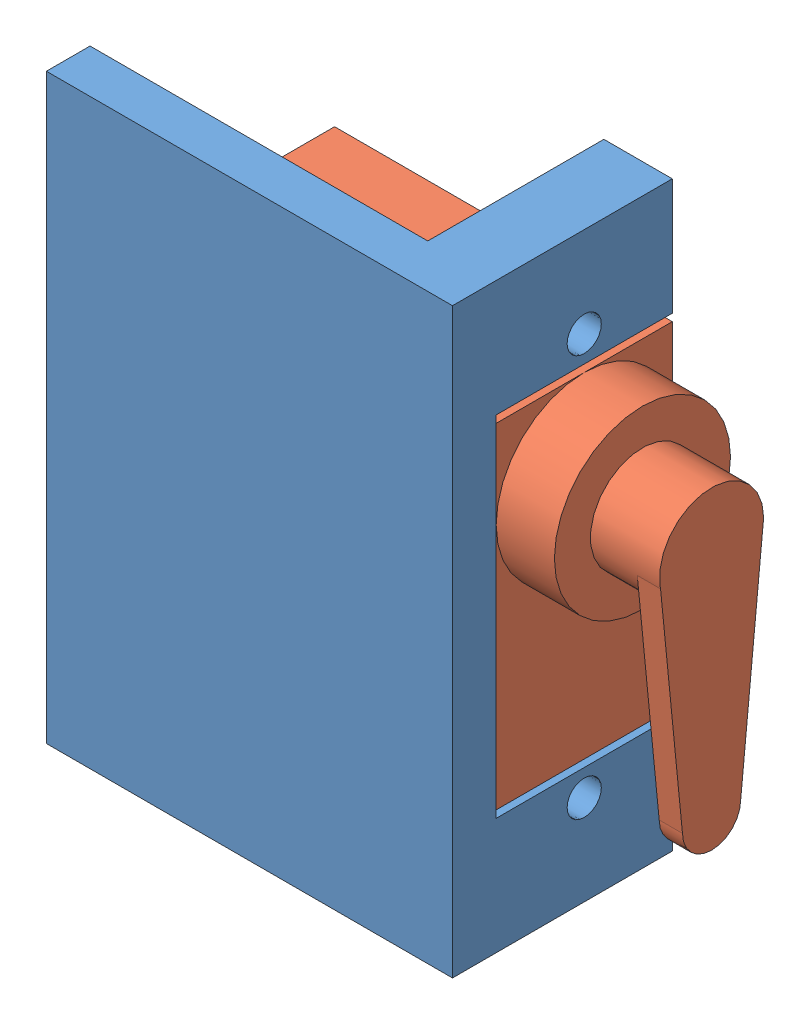
SolidWorks assembly servo_heart, configuration Default. Lengths in mm.
Overall size (36.65 40 15.1).
2 component instances, 2 part files, 6 mates.
Components (placement in the parent):
- servo_holder-1: servo_holder [Default] at origin size (27.9 40 15.1)
- servo-1: servo [Default] at (-18.5 20 -6.05) x (0 -1 0) z (0 0 1) size (32.5 31.95 12.1)
Mates (geometry in assembly coordinates):
- Coincident1: coincident aligned: plane of servo_holder-1 through (0 0 0) normal (0 0 1)
- Coincident2: coincident aligned: plane of servo_holder-1 through (0 0 0) normal (0 1 0)
- Coincident3: coincident aligned: plane of servo_holder-1 through (0 0 0) normal (1 0 0)
- Coincident8: coincident: plane of servo_holder-1 through (-23.2 40 0) normal (0 0 -1); plane of servo-1 through (4.7 8.4837 0) normal (0 0 1)
- Coincident9: coincident: plane of servo_holder-1 through (0 40 -12.1) normal (-1 0 0); plane of servo-1 through (0 36.2337 0) normal (1 0 0)
- Concentric1: concentric aligned: cylinder of servo_holder-1 through (-3.3234 33.8 -6.05) axis (1 0 0) radius 1.175; cylinder of servo-1 through (-5.1284 33.8 -6.05) axis (1 0 0) radius 1
